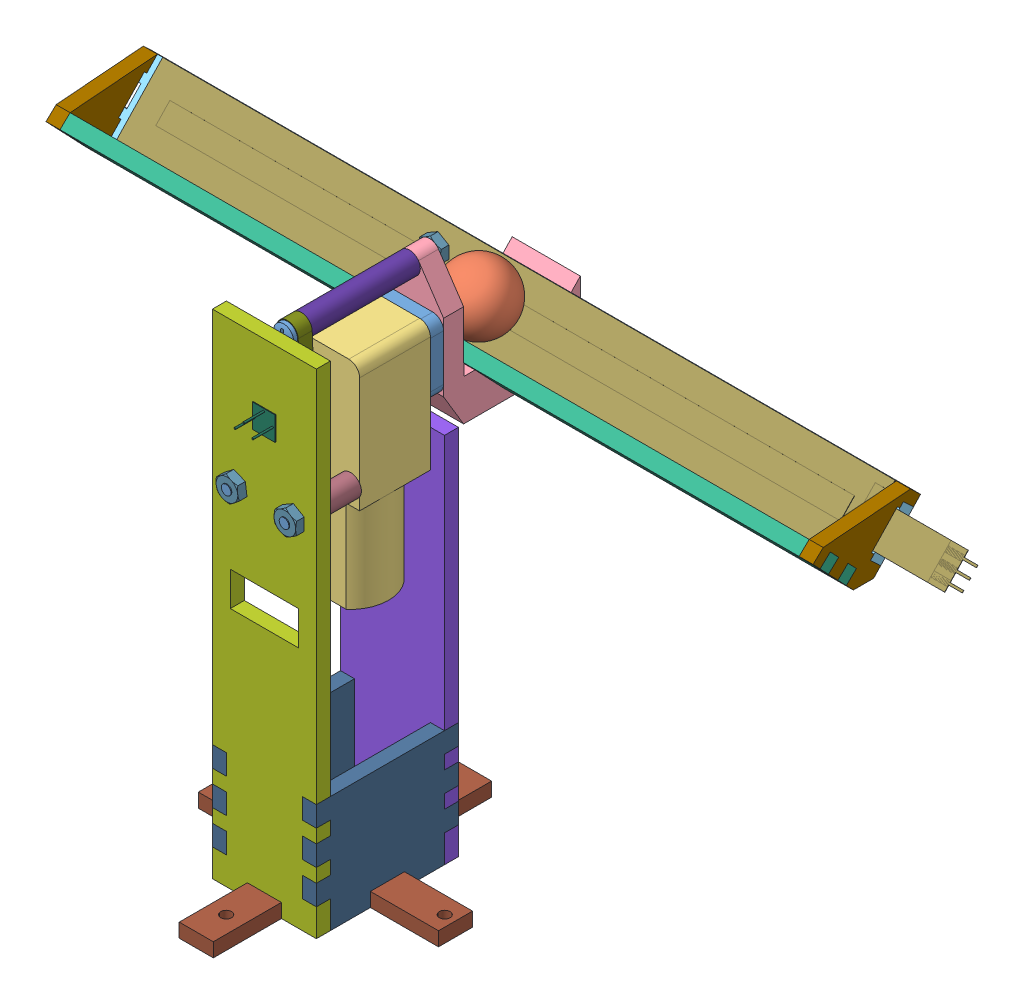
SolidWorks assembly paddle_asy, configuration Default. Lengths in mm.
Overall size (631.29 237.67 102.75).
31 component instances, 19 part files, 39 mates.
Components (placement in the parent):
- motor_interface-1: motor_interface [Default] at origin size (410.18 237.67 102.75)
- ball-1: ball [Default] at (-0.3256 0.0696 -20.6647) size (19.05 19.05 19.05)
- motor-1: motor [Default] at origin size (410.18 237.67 102.75)
- v_paddle_adapter-1: v_paddle_adapter [Default] at origin size (410.18 237.67 102.75)
- v_paddle_main-1: v_paddle_main [Default] at origin size (410.18 237.67 102.75)
- v_paddle_support-1: v_paddle_support [Default] at origin size (410.18 237.67 102.75)
- motor_support_back-1: motor_support_back [Default] at origin size (410.18 237.67 102.75)
- motor_support_front-1: motor_support_front [Default] at origin size (410.18 237.67 102.75)
- v_paddle_side_support-1: v_paddle_side_support [Default] at origin size (410.18 237.67 102.75)
- v_paddle_side_support-2: v_paddle_side_support [Default] at (-221.11 0 0) size (410.18 237.67 102.75)
- motor_support_side-1: motor_support_side [Default] at origin size (410.18 237.67 102.75)
- motor_support_side-2: motor_support_side [Default] at (-26.41 0 0) size (410.18 237.67 102.75)
- motor_support_bottom_mount-1: motor_support_bottom_mount [Default] at origin size (410.18 237.67 102.75)
- linear_potentiometer-1: linear_potentiometer [Default] at (1 -6.5694 -27.5705) x (1 0 0) z (0 -0.724095 0.6897) size (244 0.7 20)
- motor_support_spacer-1: motor_support_spacer [Default] at (8.5 -20.23 25.8) x (-0.656793 0.754071 0) z (0.754071 0.656793 0) size (6.35 12.7 6.35)
- motor_support_spacer-2: motor_support_spacer [Default] at (-8.5 -20.23 25.8) x (-1 0 0) z (0 1 0) size (6.35 12.7 6.35)
- machine screw nut hex_1_ai-1: machine screw nut hex_1_ai [MSHXNUT 0.112-48-S-N] at (8.5 -20.23 45.0992) size (6.35 7.33 2.49)
- machine screw nut hex_1_ai-2: machine screw nut hex_1_ai [MSHXNUT 0.112-48-S-N] at (-8.5 -20.23 45.0992) x (0.991212 0.132283 0) z (0 0 1) size (6.35 7.33 2.49)
- rot_pot-1: rot_pot [Default] at origin size (410.18 237.67 102.75)
- rotary_transfer_linkage-1: rotary_transfer_linkage [Default] at origin size (410.18 237.67 102.75)
- rotary_transfer_spacer-1: rotary_transfer_spacer [Default] at (0 19.1929 0) x (1 0 0) z (0 -1 0) size (6.35 31.75 6.35)
- dowel pin (hardened production)_ai-1: dowel pin (hardened production)_ai [ASME B18.8.2 - 0.1252x0.375] at (6 6 3.6455) x (0 0 -1) z (0.889994 -0.455972 0) size (9.53 3.18 3.18)
- dowel pin (hardened production)_ai-2: dowel pin (hardened production)_ai [ASME B18.8.2 - 0.1252x0.375] at (-6 6 3.6455) x (0 0 -1) z (1 0 0) size (9.53 3.18 3.18)
- dowel pin (hardened production)_ai-3: dowel pin (hardened production)_ai [ASME B18.8.2 - 0.1252x0.25] at (6.825 -1.6274 -32.2777) x (0 -0.6897 -0.724095) z (0.724095 -0.499409 0.475687) size (6.35 3.18 3.18)
- dowel pin (hardened production)_ai-5: dowel pin (hardened production)_ai [ASME B18.8.2 - 0.1252x0.25] at (6.825 -11.5113 -22.8633) x (0 -0.6897 -0.724095) z (0.724095 -0.499409 0.475687) size (6.35 3.18 3.18)
- dowel pin (hardened production)_ai-6: dowel pin (hardened production)_ai [ASME B18.8.2 - 0.1252x0.25] at (-6.825 -11.5113 -22.8633) x (0 -0.6897 -0.724095) z (0.724095 -0.499409 0.475687) size (6.35 3.18 3.18)
- dowel pin (hardened production)_ai-7: dowel pin (hardened production)_ai [ASME B18.8.2 - 0.1252x0.25] at (-6.825 -1.6274 -32.2777) x (0 -0.6897 -0.724095) z (0.843718 -0.388685 0.370222) size (6.35 3.18 3.18)
- machine screw nut hex_1_ai-3: machine screw nut hex_1_ai [MSHXNUT 0.112-48-S-N] at (0 19.1929 -5.8795) size (6.35 7.33 2.49)
- binding head screw_1_ai-7: binding head screw_1_ai [CR-BHMS 0.112-48x1.75x1.75-N] at (0 19.1929 37.5872) x (0 0 -1) z (1 0 0) size (46.15 5.97 5.97)
- binding head screw_1_ai-8: binding head screw_1_ai [CR-BHMS 0.112-48x1.75x1.75-N] at (-8.5 -20.23 -0.8372) x (0 0 1) z (-1 0 0) size (46.15 5.97 5.97)
- binding head screw_1_ai-9: binding head screw_1_ai [CR-BHMS 0.112-48x1.75x1.75-N] at (8.5 -20.23 -0.8372) x (0 0 1) z (-1 0 0) size (46.15 5.97 5.97)
Mates (geometry in assembly coordinates):
- Coincident2: coincident aligned: plane of v_paddle_main-1 through (-112.61 -13.8103 -20.6735) normal (-1 0 0); plane of v_paddle_side_support-2 through (-112.61 0 0) normal (-1 0 0)
- Coincident4: coincident aligned: plane of motor_support_back-1 through (-15.26 21.0179 42.61) normal (-1 0 0); plane of motor_support_side-2 through (-15.26 0 0) normal (-1 0 0)
- Coincident7: coincident anti-aligned: plane of v_paddle_main-1 through (0 -16.8939 -17.7364) normal (0 0.6897 0.724095); plane of linear_potentiometer-1 through (1 -6.5694 -27.5705) normal (0 -0.6897 -0.724095)
- Coincident10: coincident aligned: plane of v_paddle_main-1 through (-112.61 -13.8103 -20.6735) normal (0 -0.724095 0.6897); plane of linear_potentiometer-1 through (108.5 -13.3965 -20.239) normal (0 -0.724095 0.6897)
- Coincident11: coincident anti-aligned: plane of v_paddle_side_support-1 through (108.5 0 0) normal (-1 0 0); plane of linear_potentiometer-1 through (108.5 -13.3965 -20.239) normal (1 0 0)
- Coincident12: coincident aligned: plane of motor_support_back-1 through (-15.26 21.0179 42.61) normal (-1 0 0); plane of motor_support_side-2 through (-15.26 0 0) normal (-1 0 0)
- Coincident13: coincident aligned: plane of motor_support_front-1 through (0 0 0.89) normal (0 0 -1); plane of motor_support_side-2 through (-15.26 0 0.89) normal (0 0 -1)
- Coincident14: coincident aligned: plane of motor_support_front-1 through (-15.26 -123.8335 0.89) normal (0 -1 0); plane of motor_support_side-2 through (-15.26 -123.8335 0) normal (0 -1 0)
- Concentric1: concentric aligned: cylinder of motor_support_back-1 through (-8.5 -20.23 42.61) axis (0 0 -1) radius 1.5; cylinder of motor_support_spacer-2 through (-8.5 -20.23 38.5) axis (0 0 -1) radius 1.5875
- Coincident15: coincident anti-aligned: plane of motor_support_back-1 through (0 0 38.5) normal (0 0 -1); plane of motor_support_spacer-2 through (-8.5 -20.23 38.5) normal (0 0 1)
- Concentric2: concentric aligned: cylinder of motor_support_back-1 through (8.5 -20.23 42.61) axis (0 0 -1) radius 1.5; cylinder of motor_support_spacer-1 through (8.5 -20.23 38.5) axis (0 0 -1) radius 1.5875
- Coincident16: coincident anti-aligned: plane of motor_support_back-1 through (0 0 38.5) normal (0 0 -1); plane of motor_support_spacer-1 through (8.5 -20.23 38.5) normal (0 0 1)
- Concentric6: concentric aligned: cylinder of motor_support_front-1 through (8.5 -20.23 0.89) axis (0 0 1) radius 1.5; cylinder of machine screw nut hex_1_ai-1 through (8.5 -20.23 20.0617) axis (0 0 1) radius 1.4224
- Concentric7: concentric aligned: cylinder of motor_support_front-1 through (-8.5 -20.23 0.89) axis (0 0 1) radius 1.5; cylinder of machine screw nut hex_1_ai-2 through (-8.5 -20.23 20.0617) axis (0 0 1) radius 1.4224
- Coincident22: coincident anti-aligned: plane of motor_support_back-1 through (0 0 42.61) normal (0 0 1); plane of machine screw nut hex_1_ai-1 through (8.5 -16.5638 42.61) normal (0 0 -1)
- Coincident23: coincident anti-aligned: plane of motor_support_back-1 through (0 0 42.61) normal (0 0 1); plane of machine screw nut hex_1_ai-2 through (-8.985 -16.596 42.61) normal (0 0 -1)
- Coincident24: coincident aligned: plane of v_paddle_support-1 through (0 0.9205 -0.9664) normal (0 -0.6897 0.724095); plane of v_paddle_side_support-2 through (-112.61 -6.41 -7.9486) normal (0 -0.6897 0.724095)
- Coincident25: coincident aligned: plane of v_paddle_main-1 through (0 -19.7286 -20.7124) normal (0 -0.6897 -0.724095); plane of v_paddle_side_support-2 through (-112.61 -2.1631 -37.4435) normal (0 -0.6897 -0.724095)
- Concentric8: concentric anti-aligned: cylinder of rotary_transfer_linkage-1 through (0 19.1929 31.75) axis (0 0 1) radius 1.5875; cylinder of rotary_transfer_spacer-1 through (0 19.1929 31.75) axis (0 0 -1) radius 1.5875
- Coincident26: coincident anti-aligned: plane of rotary_transfer_linkage-1 through (0 19.1929 31.75) normal (0 0 -1); plane of rotary_transfer_spacer-1 through (0 19.1929 31.75) normal (0 0 1)
- Concentric91: concentric aligned: cylinder of dowel pin (hardened production)_ai-1 through (6 6 9.9955) axis (0 0 1) radius 1.59; cylinder of v_paddle_adapter-1 through (6 6 -10.5496) axis (0 0 1) radius 1.5875
- Concentric10: concentric aligned: cylinder of dowel pin (hardened production)_ai-2 through (-6 6 9.9955) axis (0 0 1) radius 1.59; cylinder of v_paddle_adapter-1 through (-6 6 -10.5496) axis (0 0 1) radius 1.5875
- Coincident27: coincident aligned: plane of v_paddle_adapter-1 through (-10 10 -5.8795) normal (0 0 -1); plane of dowel pin (hardened production)_ai-1 through (6 6 -5.8795) normal (0 0 -1)
- Coincident28: coincident aligned: plane of v_paddle_adapter-1 through (-10 10 -5.8795) normal (0 0 -1); plane of dowel pin (hardened production)_ai-2 through (-6 6 -5.8795) normal (0 0 -1)
- Concentric11: concentric aligned: cylinder of v_paddle_main-1 through (6.825 -11.3519 -42.4871) axis (0 0.6897 0.724095) radius 1.4859; cylinder of dowel pin (hardened production)_ai-3 through (6.825 2.7521 -27.6797) axis (0 0.6897 0.724095) radius 1.59
- Concentric12: concentric aligned: cylinder of v_paddle_main-1 through (6.825 -21.2358 -33.0727) axis (0 0.6897 0.724095) radius 1.4859; cylinder of dowel pin (hardened production)_ai-5 through (6.825 -7.1317 -18.2653) axis (0 0.6897 0.724095) radius 1.59
- Concentric13: concentric aligned: cylinder of v_paddle_main-1 through (-6.825 -21.2358 -33.0727) axis (0 0.6897 0.724095) radius 1.4859; cylinder of dowel pin (hardened production)_ai-6 through (-6.825 -7.1317 -18.2653) axis (0 0.6897 0.724095) radius 1.59
- Concentric14: concentric aligned: cylinder of v_paddle_main-1 through (-6.825 -11.3519 -42.4871) axis (0 0.6897 0.724095) radius 1.4859; cylinder of dowel pin (hardened production)_ai-7 through (-6.825 2.7521 -27.6797) axis (0 0.6897 0.724095) radius 1.59
- Coincident29: coincident aligned: plane of v_paddle_main-1 through (0 -16.8939 -17.7364) normal (0 0.6897 0.724095); plane of dowel pin (hardened production)_ai-7 through (-6.2442 -0.9664 -32.9073) normal (0 0.6897 0.724095)
- Coincident30: coincident aligned: plane of v_paddle_main-1 through (0 -16.8939 -17.7364) normal (0 0.6897 0.724095); plane of dowel pin (hardened production)_ai-3 through (7.5713 -1.0601 -32.8181) normal (0 0.6897 0.724095)
- Coincident31: coincident aligned: plane of v_paddle_main-1 through (0 -16.8939 -17.7364) normal (0 0.6897 0.724095); plane of dowel pin (hardened production)_ai-6 through (-6.0787 -10.944 -23.4037) normal (0 0.6897 0.724095)
- Coincident32: coincident aligned: plane of v_paddle_main-1 through (0 -16.8939 -17.7364) normal (0 0.6897 0.724095); plane of dowel pin (hardened production)_ai-5 through (7.5713 -10.944 -23.4037) normal (0 0.6897 0.724095)
- Coincident38: coincident anti-aligned: plane of v_paddle_adapter-1 through (-10 10 -5.8795) normal (0 0 -1); plane of machine screw nut hex_1_ai-3 through (0 22.8591 -5.8795) normal (0 0 1)
- Concentric95: concentric aligned: cylinder of rotary_transfer_linkage-1 through (0 19.1929 31.75) axis (0 0 1) radius 1.5875; cylinder of binding head screw_1_ai-7 through (0 19.1929 62.9872) axis (0 0 1) radius 1.4224
- Coincident39: coincident anti-aligned: plane of rotary_transfer_linkage-1 through (0 19.1929 35.86) normal (0 0 1); plane of binding head screw_1_ai-7 through (0 20.6153 35.86) normal (0 0 -1)
- Concentric96: concentric anti-aligned: cylinder of motor_support_front-1 through (-8.5 -20.23 0.89) axis (0 0 1) radius 1.5; cylinder of binding head screw_1_ai-8 through (-8.5 -20.23 -26.2372) axis (0 0 -1) radius 1.4224
- Coincident40: coincident anti-aligned: plane of motor_support_front-1 through (0 0 0.89) normal (0 0 -1); plane of binding head screw_1_ai-8 through (-8.5 -18.8076 0.89) normal (0 0 1)
- Concentric97: concentric anti-aligned: cylinder of motor_support_front-1 through (8.5 -20.23 0.89) axis (0 0 1) radius 1.5; cylinder of binding head screw_1_ai-9 through (8.5 -20.23 -26.2372) axis (0 0 -1) radius 1.4224
- Coincident41: coincident anti-aligned: plane of motor_support_front-1 through (0 0 0.89) normal (0 0 -1); plane of binding head screw_1_ai-9 through (8.5 -18.8076 0.89) normal (0 0 1)
